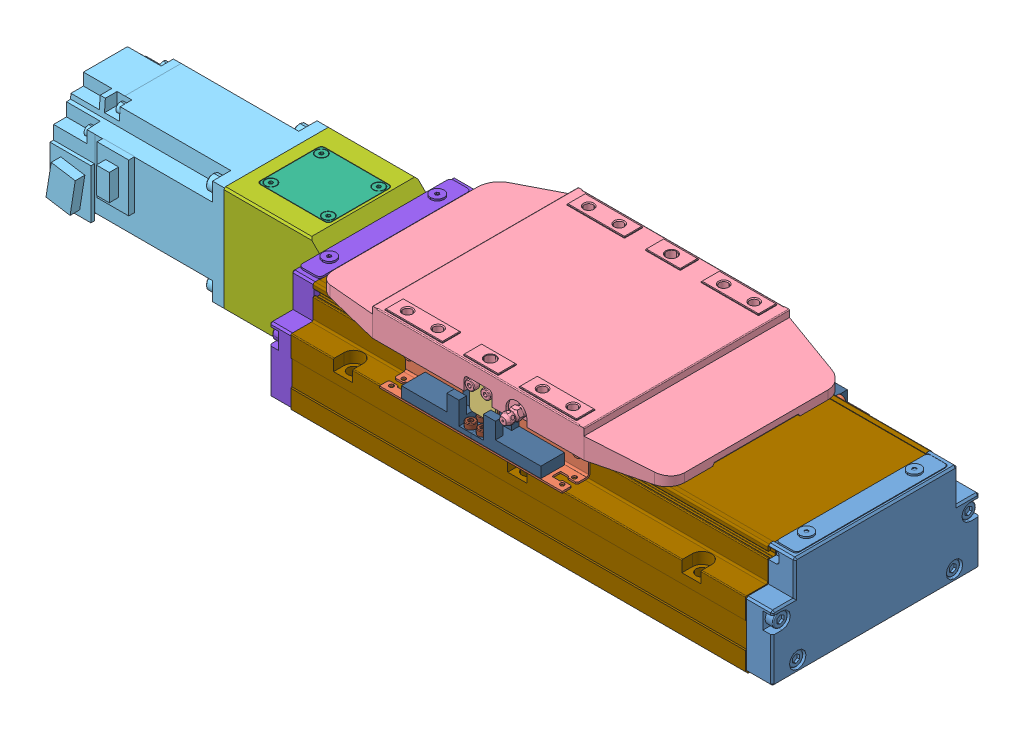
SolidWorks assembly G12-BC-400W, configuration Default. Lengths in mm.
Overall size (442.3 76 133.6).
21 component instances, 11 part files, 54 mates.
Components (placement in the parent):
- 塑胶轴承座G12^G12-BC-400W-1: 塑胶轴承座G12^G12-BC-400W [Default] at (261 0 0) size (15 58.9 119) (virtual)
- 304开关座片G5-12^G12-BC-400W-1: 304开关座片G5-12^G12-BC-400W [Default] at (209 38.5 -47.2) x (-1 0 0) z (0 0 -1) size (52.5 15.7 21) (virtual)
- 304开关座片G5-12^G12-BC-400W-2: 304开关座片G5-12^G12-BC-400W [Default] at (106.5 38.5 47.2) size (52.5 15.7 21) (virtual)
- 304感应片G8-12^G12-BC-400W-1: 304感应片G8-12^G12-BC-400W [Default] at (106.5 56.7 0) x (1 0 0) z (0 0 -1) size (15 17 1) (virtual)
- 304感应片G8-12^G12-BC-400W-2: 304感应片G8-12^G12-BC-400W [Default] at (106.5 56.7 0) x (-1 0 0) z (0 0 1) size (15 17 1) (virtual)
- 滑台G12^G12-BC-400W-1: 滑台G12^G12-BC-400W [Default] at (106.5 59.3 0) size (201.5 16.7 133.6) (virtual)
- 三菱400W^G12-BC-400W-1: 三菱400W^G12-BC-400W [Default] at (-68 32.5 0) x (0 0 1) z (0 -1 0) size (68.8 128.3 60) (virtual)
- 联轴器盖GY12^G12-BC-400W-1: 联轴器盖GY12^G12-BC-400W [Default] at origin size (40.5 2 36.5) (virtual)
- 电机座GY12-P60^G12-BC-400W-1: 电机座GY12-P60^G12-BC-400W [Default] at origin size (55 61 61) (virtual)
- 丝杆座板G12^G12-BC-400W-1: 丝杆座板G12^G12-BC-400W [Default] at origin size (20.5 58.7 119) (virtual)
- 复件 底座GY12+211^G12-BC-400W-1: 复件 底座GY12+211^G12-BC-400W [默认] x (0 0 -1) z (1 0 0) size (120 58 261) (virtual)
- 304开关座片G5-12^G12-BC-400W-3: 304开关座片G5-12^G12-BC-400W [Default] at (54 38.5 47.2) size (52.5 15.7 21) (virtual)
- 复件 复件 光电开关EE-SX674^G12-BC-400W-1: 复件 复件 光电开关EE-SX674^G12-BC-400W [默认] at (66.5 41.8 49.4) size (40 15.5 13.6) (virtual)
- 复件 复件 光电开关EE-SX674^G12-BC-400W-2: 复件 复件 光电开关EE-SX674^G12-BC-400W [默认] at (146.5 41.8 63) x (-1 0 0) z (0 0 -1) size (40 15.5 13.6) (virtual)
- 复件 复件 光电开关EE-SX674^G12-BC-400W-3: 复件 复件 光电开关EE-SX674^G12-BC-400W [默认] at (196.5 41.8 -49.4) x (-1 0 0) z (0 0 -1) size (40 15.5 13.6) (virtual)
- hexagon socket head cap screws gb-2: hexagon socket head cap screws gb [GB_FASTENER_SCREWS_HSHCS M3X5-N] at (103 47.4 52.7) x (0 -1 0) z (0 0 1) size (8 5.5 5.5)
- hexagon socket head cap screws gb-3: hexagon socket head cap screws gb [GB_FASTENER_SCREWS_HSHCS M3X5-N] at (103 47.4 59.7) x (0 -1 0) z (0 0 1) size (8 5.5 5.5)
- hexagon socket head cap screws gb-4: hexagon socket head cap screws gb [GB_FASTENER_SCREWS_HSHCS M3X5-N] at (110 47.4 59.7) x (0 -1 0) z (0 0 1) size (8 5.5 5.5)
- hexagon socket head cap screws gb-5: hexagon socket head cap screws gb [GB_FASTENER_SCREWS_HSHCS M3X5-N] at (110 47.4 52.7) x (0 -1 0) z (0 0 1) size (8 5.5 5.5)
- hexagon socket head cap screws gb-6: hexagon socket head cap screws gb [GB_FASTENER_SCREWS_HSHCS M3X5-N] at (160 47.4 -59.7) x (0 -1 0) z (0 0 1) size (8 5.5 5.5)
- hexagon socket head cap screws gb-7: hexagon socket head cap screws gb [GB_FASTENER_SCREWS_HSHCS M3X5-N] at (160 47.4 -52.7) x (0 -1 0) z (0 0 1) size (8 5.5 5.5)
Mates (geometry in assembly coordinates):
- 宽度3: width: plane of 丝杆座板G12^G12-BC-400W-1 through (-13 37.5 59.5) normal (0 0 1); plane of 丝杆座板G12^G12-BC-400W-1 through (-13 2 -59.5) normal (0 0 -1); plane of 复件 底座GY12+211^G12-BC-400W-1 through (261 12.5 -59.5) normal (0 0 -1); plane of 复件 底座GY12+211^G12-BC-400W-1 through (261 26.5 59.5) normal (0 0 1)
- 距离2: distance = 1 mm: plane of 丝杆座板G12^G12-BC-400W-1 through (-13 1 58.5) normal (0 -1 0); plane of 复件 底座GY12+211^G12-BC-400W-1 through (261 0 58.5) normal (0 -1 0)
- 重合6: coincident: plane of 丝杆座板G12^G12-BC-400W-1 through (0 0 0) normal (1 0 0); plane of 复件 底座GY12+211^G12-BC-400W-1 through (0 57 46.2) normal (-1 0 0)
- 距离3: distance = 1 mm: plane of 电机座GY12-P60^G12-BC-400W-1 through (-68 2 29.5) normal (0 -1 0); plane of 丝杆座板G12^G12-BC-400W-1 through (-13 1 58.5) normal (0 -1 0)
- 宽度4: width: plane of 复件 底座GY12+211^G12-BC-400W-1 through (261 12.5 -59.5) normal (0 0 -1); plane of 复件 底座GY12+211^G12-BC-400W-1 through (261 26.5 59.5) normal (0 0 1); plane of 电机座GY12-P60^G12-BC-400W-1 through (-68 62 30.5) normal (0 0 1); plane of 电机座GY12-P60^G12-BC-400W-1 through (-68 3 -30.5) normal (0 0 -1)
- 重合8: coincident: plane of 电机座GY12-P60^G12-BC-400W-1 through (-13 0 0) normal (1 0 0); plane of 丝杆座板G12^G12-BC-400W-1 through (-13 0 0) normal (-1 0 0)
- 宽度5: width: plane of 复件 底座GY12+211^G12-BC-400W-1 through (261 12.5 -59.5) normal (0 0 -1); plane of 复件 底座GY12+211^G12-BC-400W-1 through (261 26.5 59.5) normal (0 0 1); plane of 联轴器盖GY12^G12-BC-400W-1 through (-58.75 61 18.25) normal (0 0 1); plane of 联轴器盖GY12^G12-BC-400W-1 through (-22.25 61 -18.25) normal (0 0 -1)
- 宽度6: width: plane of 电机座GY12-P60^G12-BC-400W-1 through (-20 61 16.5) normal (-1 0 0); plane of 电机座GY12-P60^G12-BC-400W-1 through (-61 61 -16.5) normal (1 0 0); plane of 联轴器盖GY12^G12-BC-400W-1 through (-60.75 61 -16.25) normal (-1 0 0); plane of 联轴器盖GY12^G12-BC-400W-1 through (-20.25 61 16.25) normal (1 0 0)
- 重合9: coincident: plane of 联轴器盖GY12^G12-BC-400W-1 through (-58.75 63 16.25) normal (0 1 0); plane of 电机座GY12-P60^G12-BC-400W-1 through (-68 63 -29.5) normal (0 1 0)
- 距离4: distance = 0.5 mm: plane of 三菱400W^G12-BC-400W-1 through (-142.5 2.5 -30) normal (0 -1 0); plane of 电机座GY12-P60^G12-BC-400W-1 through (-68 2 29.5) normal (0 -1 0)
- 宽度7: width: plane of 电机座GY12-P60^G12-BC-400W-1 through (-68 62 30.5) normal (0 0 1); plane of 电机座GY12-P60^G12-BC-400W-1 through (-68 3 -30.5) normal (0 0 -1); plane of 三菱400W^G12-BC-400W-1 through (-142.5 62.5 -30) normal (0 0 -1); plane of 三菱400W^G12-BC-400W-1 through (-142.5 2.5 30) normal (0 0 1)
- 重合11: coincident: plane of 三菱400W^G12-BC-400W-1 through (-68 32.5 0) normal (1 0 0); plane of 电机座GY12-P60^G12-BC-400W-1 through (-68 0 0) normal (-1 0 0)
- 距离5: distance = 2.5 mm: plane of 304感应片G8-12^G12-BC-400W-2 through (112 51 56.5) normal (0 0 1); plane of 滑台G12^G12-BC-400W-1 through (45.75 76 59) normal (0 0 1)
- 宽度8: width: plane of 304感应片G8-12^G12-BC-400W-2 through (99 64 56.5) normal (-1 0 0); plane of 304感应片G8-12^G12-BC-400W-2 through (114 51 56.5) normal (1 0 0); plane of 滑台G12^G12-BC-400W-1 through (98.5 65 55.5) normal (1 0 0); plane of 滑台G12^G12-BC-400W-1 through (114.5 59.3 55.5) normal (-1 0 0)
- 距离6: distance = 10.3 mm: plane of 滑台G12^G12-BC-400W-1 through (15.75 59.3 -41.214) normal (0 -1 0); plane of 304感应片G8-12^G12-BC-400W-2 through (101 49 56.5) normal (0 -1 0)
- 距离7: distance = 76 mm: plane of 滑台G12^G12-BC-400W-1 through (15.75 76 -41.214) normal (0 1 0); plane of 复件 底座GY12+211^G12-BC-400W-1 through (261 0 58.5) normal (0 -1 0)
- 宽度9: width: plane of 滑台G12^G12-BC-400W-1 through (45.75 76 59) normal (0 0 1); plane of 滑台G12^G12-BC-400W-1 through (167.25 76 -59) normal (0 0 -1); plane of 复件 底座GY12+211^G12-BC-400W-1 through (261 12.5 -59.5) normal (0 0 -1); plane of 复件 底座GY12+211^G12-BC-400W-1 through (261 26.5 59.5) normal (0 0 1)
- 宽度10: width: plane of 304感应片G8-12^G12-BC-400W-1 through (114 64 -56.5) normal (1 0 0); plane of 304感应片G8-12^G12-BC-400W-1 through (99 51 -56.5) normal (-1 0 0); plane of 滑台G12^G12-BC-400W-1 through (114.5 59.3 -55.5) normal (-1 0 0); plane of 滑台G12^G12-BC-400W-1 through (98.5 65 -55.5) normal (1 0 0)
- 距离8: distance = 2.5 mm: plane of 304感应片G8-12^G12-BC-400W-1 through (101 51 -56.5) normal (0 0 -1); plane of 滑台G12^G12-BC-400W-1 through (167.25 76 -59) normal (0 0 -1)
- 距离9: distance = 10.3 mm: plane of 304感应片G8-12^G12-BC-400W-1 through (112 49 -56.5) normal (0 -1 0); plane of 滑台G12^G12-BC-400W-1 through (15.75 59.3 -41.214) normal (0 -1 0)
- 距离10: distance = 119.5 mm: plane of 304开关座片G5-12^G12-BC-400W-2 through (106.5 42.8 49.2) normal (-1 0 0); plane of 丝杆座板G12^G12-BC-400W-1 through (-13 0 0) normal (-1 0 0)
- 宽度11: width: plane of 复件 底座GY12+211^G12-BC-400W-1 through (261 51.25 46.2) normal (0 1 0); plane of 复件 底座GY12+211^G12-BC-400W-1 through (261 54.75 46.7) normal (0 -1 0); cylinder of 304开关座片G5-12^G12-BC-400W-2 through (110.5 53 42.2) axis (0 0 -1) radius 2.75
- 重合16: coincident: plane of 304开关座片G5-12^G12-BC-400W-2 through (106.5 42.8 49.2) normal (-1 0 0); plane of 304开关座片G5-12^G12-BC-400W-3 through (106.5 42.8 49.2) normal (1 0 0)
- 重合17: coincident: plane of 304开关座片G5-12^G12-BC-400W-2 through (159 40.8 63.2) normal (0 -1 0); plane of 304开关座片G5-12^G12-BC-400W-3 through (106.5 40.8 63.2) normal (0 -1 0)
- 重合18: coincident: plane of 复件 底座GY12+211^G12-BC-400W-1 through (261 50.75 47.2) normal (0 0 1); plane of 304开关座片G5-12^G12-BC-400W-3 through (106.5 42.8 47.2) normal (0 0 -1)
- 重合19: coincident: plane of 304开关座片G5-12^G12-BC-400W-2 through (159 56.5 48.2) normal (0 0 1); plane of 304开关座片G5-12^G12-BC-400W-3 through (106.5 56.5 48.2) normal (0 0 1)
- 重合22: coincident: plane of 304开关座片G5-12^G12-BC-400W-1 through (156.5 42.8 -47.2) normal (0 0 1); plane of 复件 底座GY12+211^G12-BC-400W-1 through (261 40 -47.2) normal (0 0 -1)
- 重合23: coincident: plane of 304开关座片G5-12^G12-BC-400W-1 through (156.5 40.8 -63.2) normal (0 -1 0); plane of 304开关座片G5-12^G12-BC-400W-2 through (159 40.8 63.2) normal (0 -1 0)
- 距离13: distance = 1 mm: plane of 塑胶轴承座G12^G12-BC-400W-1 through (276 1 58.5) normal (0 -1 0); plane of 复件 底座GY12+211^G12-BC-400W-1 through (261 0 58.5) normal (0 -1 0)
- 宽度12: width: plane of 塑胶轴承座G12^G12-BC-400W-1 through (276 37.5 59.5) normal (0 0 1); plane of 塑胶轴承座G12^G12-BC-400W-1 through (276 2 -59.5) normal (0 0 -1); plane of 复件 底座GY12+211^G12-BC-400W-1 through (261 12.5 -59.5) normal (0 0 -1); plane of 复件 底座GY12+211^G12-BC-400W-1 through (261 26.5 59.5) normal (0 0 1)
- 重合25: coincident: plane of 塑胶轴承座G12^G12-BC-400W-1 through (261 0 0) normal (-1 0 0); plane of 复件 底座GY12+211^G12-BC-400W-1 through (261 57 46.2) normal (1 0 0)
- 宽度13: width: plane of 304开关座片G5-12^G12-BC-400W-3 through (54 42.8 49.2) normal (-1 0 0); plane of 304开关座片G5-12^G12-BC-400W-2 through (159 42.8 49.2) normal (1 0 0); plane of 304感应片G8-12^G12-BC-400W-2 through (99 64 56.5) normal (-1 0 0); plane of 304感应片G8-12^G12-BC-400W-2 through (114 51 56.5) normal (1 0 0)
- 距离14: distance = 67 mm: plane of 塑胶轴承座G12^G12-BC-400W-1 through (276 0 0) normal (1 0 0); plane of 304开关座片G5-12^G12-BC-400W-1 through (209 42.8 -49.2) normal (1 0 0)
- 重合26: coincident: plane of 304开关座片G5-12^G12-BC-400W-3 through (106.5 41.8 49.2) normal (0 1 0); plane of 复件 复件 光电开关EE-SX674^G12-BC-400W-1 through (106.5 41.8 63) normal (0 -1 0)
- 同心1: concentric: cylinder of 304开关座片G5-12^G12-BC-400W-3 through (103 43.5 52.7) axis (0 -1 0) radius 1.23; cylinder of 复件 复件 光电开关EE-SX674^G12-BC-400W-1 through (103 30.8 52.7) axis (0 1 0) radius 1.75
- 同心2: concentric: cylinder of 304开关座片G5-12^G12-BC-400W-3 through (103 43.5 59.7) axis (0 -1 0) radius 1.23; cylinder of 复件 复件 光电开关EE-SX674^G12-BC-400W-1 through (103 30.8 59.7) axis (0 1 0) radius 1.75
- 同心3: concentric: cylinder of 304开关座片G5-12^G12-BC-400W-2 through (110 43.5 59.7) axis (0 -1 0) radius 1.23; cylinder of 复件 复件 光电开关EE-SX674^G12-BC-400W-2 through (110 30.8 59.7) axis (0 1 0) radius 1.75
- 同心4: concentric: cylinder of 304开关座片G5-12^G12-BC-400W-2 through (110 43.5 52.7) axis (0 -1 0) radius 1.23; cylinder of 复件 复件 光电开关EE-SX674^G12-BC-400W-2 through (110 30.8 52.7) axis (0 1 0) radius 1.75
- 重合28: coincident: plane of 304开关座片G5-12^G12-BC-400W-2 through (159 41.8 49.2) normal (0 1 0); plane of 复件 复件 光电开关EE-SX674^G12-BC-400W-2 through (106.5 41.8 49.4) normal (0 -1 0)
- 重合29: coincident: plane of 304开关座片G5-12^G12-BC-400W-1 through (156.5 41.8 -49.2) normal (0 1 0); plane of 复件 复件 光电开关EE-SX674^G12-BC-400W-3 through (156.5 41.8 -63) normal (0 -1 0)
- 同心5: concentric: cylinder of 304开关座片G5-12^G12-BC-400W-1 through (160 43.5 -52.7) axis (0 -1 0) radius 1.23; cylinder of 复件 复件 光电开关EE-SX674^G12-BC-400W-3 through (160 30.8 -52.7) axis (0 1 0) radius 1.75
- 同心6: concentric: cylinder of 304开关座片G5-12^G12-BC-400W-1 through (160 43.5 -59.7) axis (0 -1 0) radius 1.23; cylinder of 复件 复件 光电开关EE-SX674^G12-BC-400W-3 through (160 30.8 -59.7) axis (0 1 0) radius 1.75
- 重合30: coincident: plane of 复件 复件 光电开关EE-SX674^G12-BC-400W-1 through (99.5 44.4 63) normal (0 1 0); plane of hexagon socket head cap screws gb-2 through (103 44.4 52.7) normal (0 -1 0)
- 同心7: concentric: cylinder of 复件 复件 光电开关EE-SX674^G12-BC-400W-1 through (103 30.8 52.7) axis (0 1 0) radius 1.75; cylinder of hexagon socket head cap screws gb-2 through (103 39.4 52.7) axis (0 1 0) radius 1.5
- 重合31: coincident: plane of 复件 复件 光电开关EE-SX674^G12-BC-400W-1 through (99.5 44.4 63) normal (0 1 0); plane of hexagon socket head cap screws gb-3 through (103 44.4 59.7) normal (0 -1 0)
- 同心8: concentric: cylinder of 复件 复件 光电开关EE-SX674^G12-BC-400W-1 through (103 30.8 59.7) axis (0 1 0) radius 1.75; cylinder of hexagon socket head cap screws gb-3 through (103 39.4 59.7) axis (0 1 0) radius 1.5
- 重合32: coincident: plane of 复件 复件 光电开关EE-SX674^G12-BC-400W-2 through (113.5 44.4 49.4) normal (0 1 0); plane of hexagon socket head cap screws gb-4 through (110 44.4 59.7) normal (0 -1 0)
- 同心9: concentric: cylinder of 复件 复件 光电开关EE-SX674^G12-BC-400W-2 through (110 30.8 59.7) axis (0 1 0) radius 1.75; cylinder of hexagon socket head cap screws gb-4 through (110 44.4 59.7) axis (0 1 0) radius 2.75
- 重合33: coincident: plane of 复件 复件 光电开关EE-SX674^G12-BC-400W-2 through (113.5 44.4 49.4) normal (0 1 0); plane of hexagon socket head cap screws gb-5 through (110 44.4 52.7) normal (0 -1 0)
- 同心10: concentric: cylinder of 复件 复件 光电开关EE-SX674^G12-BC-400W-2 through (110 30.8 52.7) axis (0 1 0) radius 1.75; cylinder of hexagon socket head cap screws gb-5 through (110 39.4 52.7) axis (0 1 0) radius 1.5
- 同心111: concentric: cylinder of 复件 复件 光电开关EE-SX674^G12-BC-400W-3 through (160 30.8 -59.7) axis (0 1 0) radius 1.75; cylinder of hexagon socket head cap screws gb-6 through (160 39.4 -59.7) axis (0 1 0) radius 1.5
- 重合341: coincident: plane of 复件 复件 光电开关EE-SX674^G12-BC-400W-3 through (163.5 44.4 -63) normal (0 1 0); plane of hexagon socket head cap screws gb-6 through (160 44.4 -59.7) normal (0 -1 0)
- 同心121: concentric: cylinder of 复件 复件 光电开关EE-SX674^G12-BC-400W-3 through (160 30.8 -52.7) axis (0 1 0) radius 1.75; cylinder of hexagon socket head cap screws gb-7 through (160 39.4 -52.7) axis (0 1 0) radius 1.5
- 重合351: coincident: plane of 复件 复件 光电开关EE-SX674^G12-BC-400W-3 through (163.5 44.4 -63) normal (0 1 0); plane of hexagon socket head cap screws gb-7 through (160 44.4 -52.7) normal (0 -1 0)
